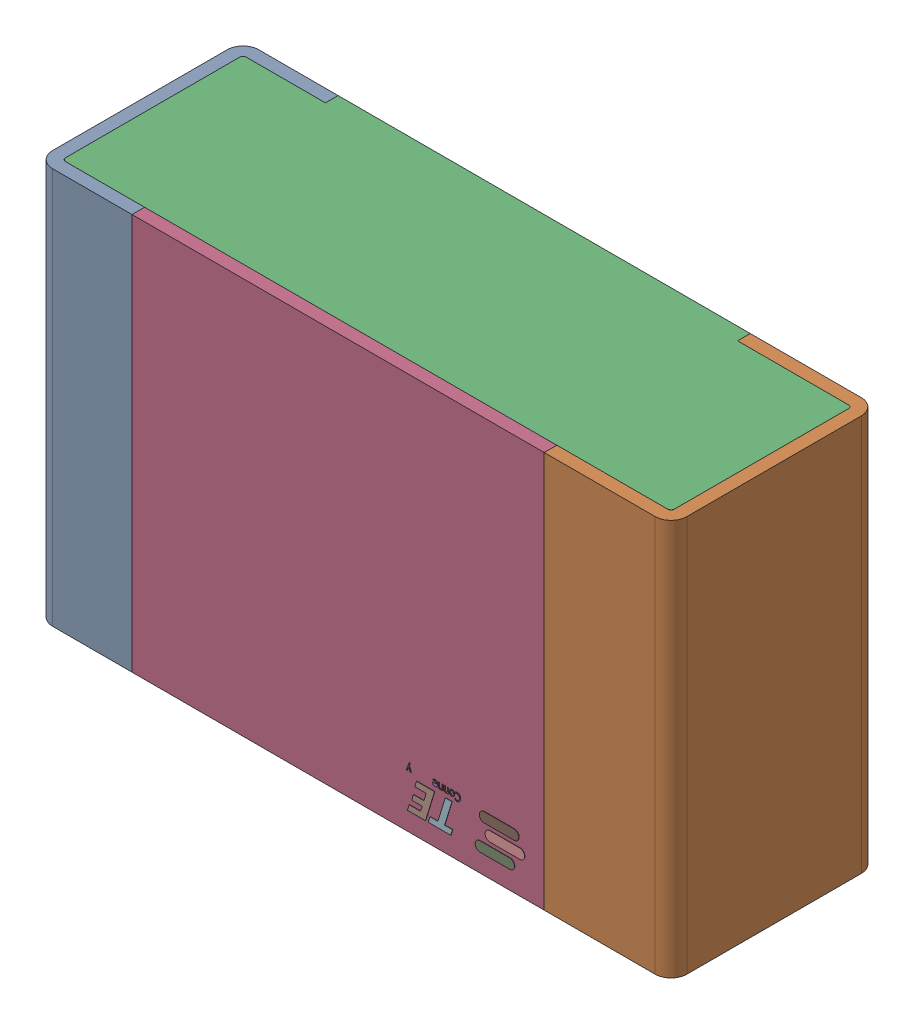
SolidWorks assembly RLH1.step, configuration Default. Lengths in mm.
Overall size (2 1.25 0.65).
5 component instances, 4 part files, 0 mates.
Components (placement in the parent):
- Res_TE_Connectivity_CPF0805B66R5E1_eec.step-1: Res_TE_Connectivity_CPF0805B66R5E1_eec.step [Default] at (5.191 31.181 0) x (-1 0 0) z (0 0 1) size (2 1.25 0.65)
  - 1.step-1: 1.step [Default] at origin size (2 1.25 0.65)
  - 2.step-1: 2.step [Default] at origin size (1.92 1.25 0.61)
  - 3.step-1: 3.step [Default] at origin size (1.3 1.25 0.04)
  - TE connectivity Logo 1 (2).step-1: TE connectivity Logo 1 (2).step [Default] at (5.4285 0.313 0.551) x (-1 0 0) z (0 0 1) size (0.37 0.13 0.11)
